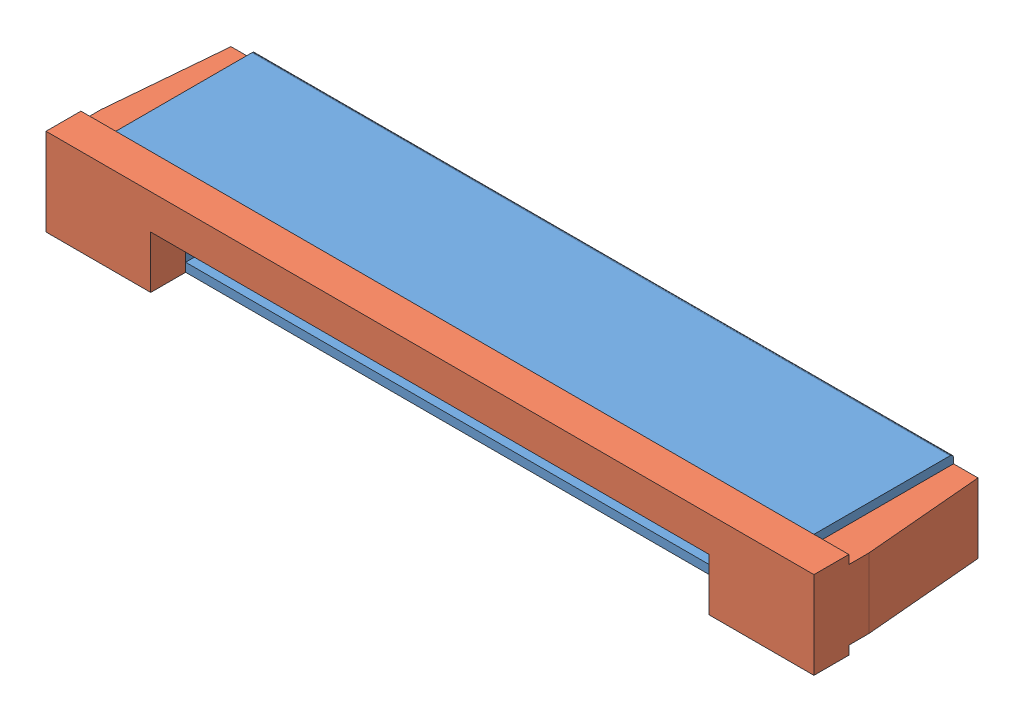
SolidWorks assembly 15 Pin Ribbon Block Assem, configuration Default. Lengths in mm.
Overall size (22 2.5 7).
2 component instances, 2 part files, 3 mates.
Components (placement in the parent):
- 15 Pin Ribbon Block-1: 15 Pin Ribbon Block [Default] at (8.217 10.8197 14.6952) size (20 2.5 6)
- Ribbon Clamp-1: Ribbon Clamp [Default] at (8.217 10.8197 14.6952) size (22 2.5 5)
Mates (geometry in assembly coordinates):
- Coincident1: coincident: 15 Pin Ribbon Block-1, Ribbon Clamp-1
- Coincident2: coincident: 15 Pin Ribbon Block-1, Ribbon Clamp-1
- Distance1: distance = 0 mm: 15 Pin Ribbon Block-1, Ribbon Clamp-1
